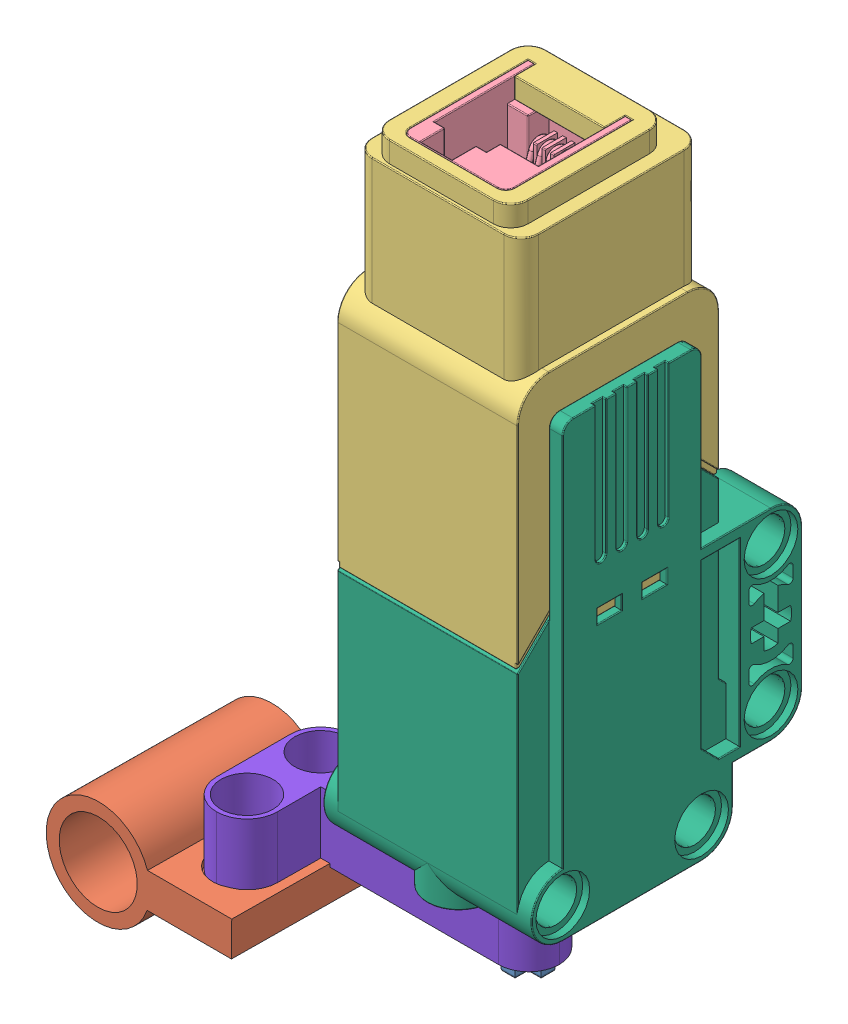
SolidWorks assembly Assem1, configuration Default. Lengths in mm.
Overall size (54.27 91.78 54.45).
11 component instances, 8 part files, 4 mates.
Components (placement in the parent):
- Shaft-1: Shaft [Default] at (8.3043 9.9175 -4.409) size (4.6 23 4.6)
- Pencil Holder-1: Pencil Holder [Default] at (-26.469 10.1241 10.3734) x (1 0 0) z (0 0.999962 -0.008727) size (24.29 40 15)
- LEGOEV3MEDIUMMOTOR-1: LEGOEV3MEDIUMMOTOR [Default] at (8.3043 78.2315 -4.409) x (1 0 0) z (0 -1 0) size (24 31.22 72.5)
  - 99455.stp-1: 99455.stp [Default] at origin size (24 31.22 72.5)
    - 99535c01.stp-1: 99535c01.stp [Default] at origin size (24 31.22 72.4)
      - 99534-White.stp-1: 99534-White.stp [Default] at origin size (22.4 23.2 44.8)
      - 54732b-LtBluishGray.stp-1: 54732b-LtBluishGray.stp [Default] at (0 0.8 -16) x (-1 0 0) z (0 0 -1) size (12 14.56 14.4)
      - 99542-MilkyWhite.stp-1: 99542-MilkyWhite.stp [Default] at (0 0 48.4) x (1 0 0) z (0 0 -1) size (20.8 20.8 2.4)
      - 99535-LtBluishGray.stp-1: 99535-LtBluishGray.stp [Default] at (0 0 28.4) size (24 31.22 52)
    - 99543-Red.stp-1: 99543-Red.stp [Default] at (0 0 47.7) size (16 16 12.4)
- L-1: L [Default] at (-19.1499 11.6298 -7.959) x (0 0 1) z (-1 0 0) size (15.5 7.5 31)
Mates (geometry in assembly coordinates):
- Coincident1: coincident anti-aligned: line of Shaft-1 through (9.1043 32.6175 -3.609) axis (0 -1 0); line of LEGOEV3MEDIUMMOTOR-1/99455.stp-1/99543-Red.stp-1 through (9.1043 21.7315 -3.609) axis (0 1 0)
- Coincident2: coincident anti-aligned: plane of Shaft-1 through (6.0043 32.9175 -3.609) normal (0 0 1); plane of LEGOEV3MEDIUMMOTOR-1/99455.stp-1/99543-Red.stp-1 through (6.0416 21.7315 -3.609) normal (0 0 -1)
- Parallel4: parallel anti-aligned: plane of Shaft-1 through (7.5043 32.9175 -6.709) normal (0 0 -1); plane of L-1 through (9.1043 11.6298 -6.759) normal (0 0 1)
- Coincident11: coincident anti-aligned: line of Shaft-1 through (9.1043 32.6175 -5.209) axis (0 -1 0); line of L-1 through (9.1043 11.6298 -5.209) axis (0 1 0)
